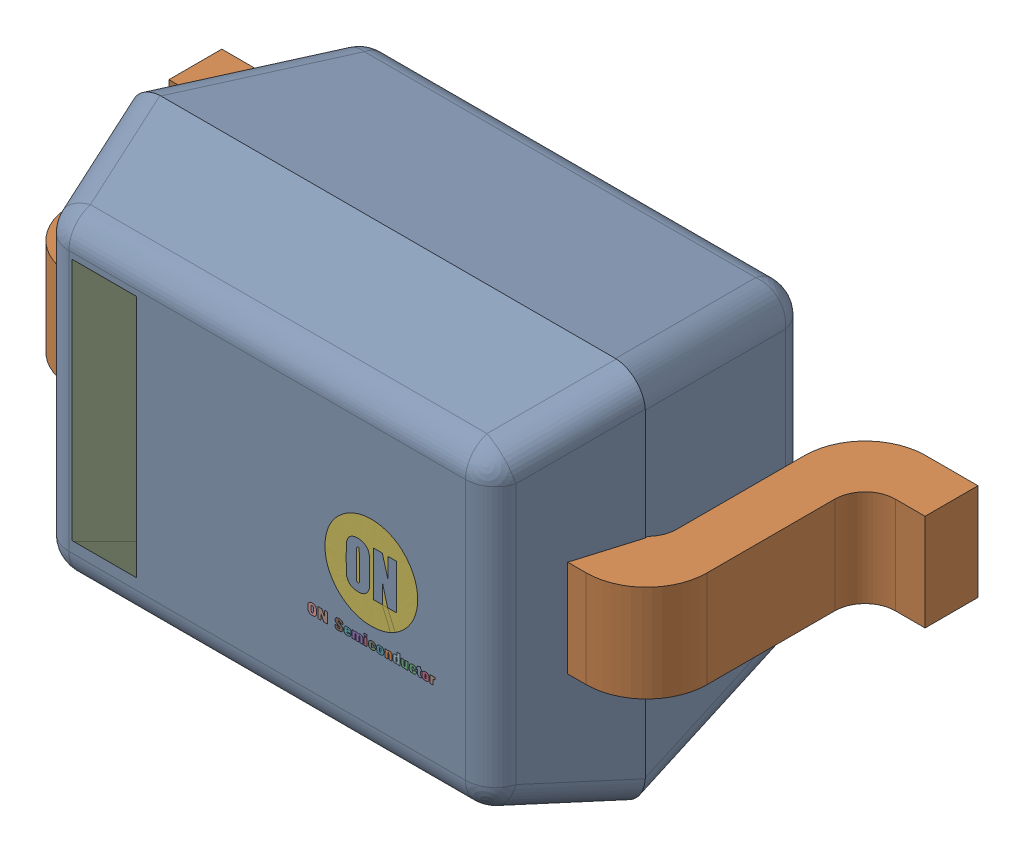
SolidWorks assembly Diode_ON_Semiconductor_NSR02100HT1G_eec, configuration Défaut. Lengths in mm.
Overall size (2.5 1.25 1.12).
4 component instances, 4 part files, 0 mates.
Components (placement in the parent):
- 1-1: 1 [Défaut] at (0 0 0.05) size (1.7 1.25 1.08)
- 2-1: 2 [Défaut] x (1 0 0) z (0 -1 0) size (2.5 0.9 0.32)
- ON Semiconductor-1: ON Semiconductor [Défaut] at (0.2865 -0.4575 1.0977) size (0.43 0.38 0.01)
- bar-1: bar [Défaut] at (0 0 1.1) size (0.22 0.81 0)
